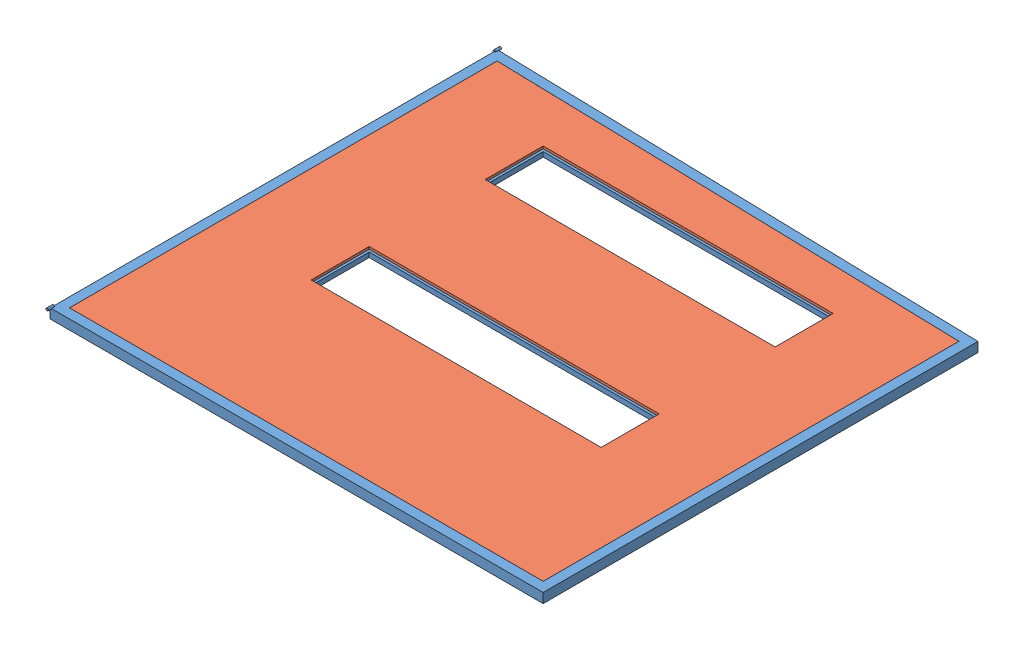
SolidWorks assembly LRS_WALL_ASSEMBLY, configuration Default. Lengths in mm.
Overall size (2597.15 57.15 2381.89).
2 component instances, 2 part files, 3 mates.
Components (placement in the parent):
- LSR_WALL FRAME_100.38-1: LSR_WALL FRAME_100.38 [Default] at (-286.4469 1365.0904 3128.6531) size (2597.15 57.15 2381.89)
- LS WALL_INSULATION-1: LS WALL_INSULATION [Default] at (983.8914 1339.6904 1979.9894) x (0 0 1) z (-1 0 0) size (2247.14 50.8 2489.2)
Mates (geometry in assembly coordinates):
- Coincident1: coincident anti-aligned: plane of LSR_WALL FRAME_100.38-1 through (2228.1531 1390.4904 866.1028) normal (-1 0 0); plane of LS WALL_INSULATION-1 through (2228.1531 1390.4904 918.0911) normal (1 0 0)
- Coincident2: coincident aligned: plane of LSR_WALL FRAME_100.38-1 through (2281.5931 1390.4904 3154.0531) normal (0 1 0); plane of LS WALL_INSULATION-1 through (983.8914 1390.4904 1979.9894) normal (0 1 0)
- Coincident3: coincident anti-aligned: plane of LSR_WALL FRAME_100.38-1 through (2281.5931 1390.4904 3103.2531) normal (0 0 -1); plane of LS WALL_INSULATION-1 through (2228.1531 1390.4904 3103.2531) normal (0 0 1)
